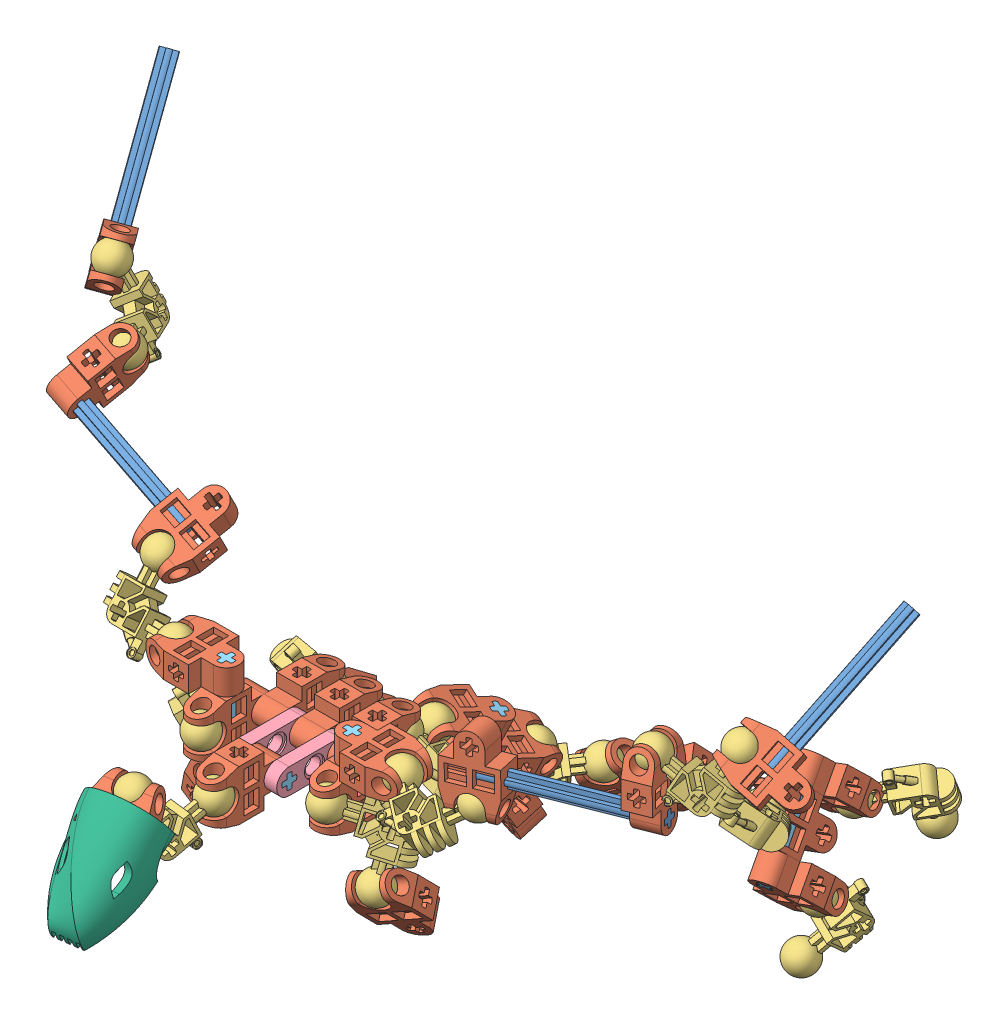
SolidWorks assembly lizard guy, configuration Default. Lengths in mm.
Overall size (163.73 140.06 167.64).
55 component instances, 6 part files, 111 mates.
Components (placement in the parent):
- cross axle 6-1: cross axle 6 [Default] at (25.195 14.8758 24.0867) x (0 1 0) z (0 0 1) size (3 30 3)
- the hand-1: the hand [Default] at (15.195 14.8758 16.5867) x (0 1 0) z (0 0 -1) size (10 5 15)
- the hand-2: the hand [Default] at (0.195 14.8758 16.5867) x (0 1 0) z (0 0 -1) size (10 5 15)
- the hand-3: the hand [Default] at (7.774 20.7052 60.2675) x (0.981668 -0.041567 -0.186012) z (-0.127151 0.584205 -0.801584) size (10 5 15)
- the hand-4: the hand [Default] at (20.195 14.8758 31.5867) x (0 -1 0) z (0 0 1) size (10 5 15)
- the hand-5: the hand [Default] at (0.195 14.8758 31.5867) x (0 1 0) z (0 0 1) size (10 5 15)
- the hand-6: the hand [Default] at (12.695 14.8758 41.5867) x (0 1 0) z (0 0 1) size (10 5 15)
- link 2x2-1: link 2x2 [Default] at (-10.1427 12.5461 28.3297) x (0.78377 0.232967 0.575701) z (0.438972 -0.863547 -0.248175) size (17.5 6 18.1)
- link 2x2-2: link 2x2 [Default] at (30.8875 12.6779 28.7903) x (-0.81925 0.219789 0.529644) z (-0.048801 -0.947003 0.317496) size (17.5 6 18.1)
- link 2x2-3: link 2x2 [Default] at (-6.8535 13.6326 11.3886) x (0.954853 0.124318 0.269818) z (0.238465 -0.862394 -0.446554) size (17.5 6 18.1)
- link 2x2-4: link 2x2 [Default] at (26.8546 10.8703 13.8459) x (-0.915958 0.400551 0.02408) z (-0.180749 -0.358261 -0.915958) size (17.5 6 18.1)
- link 2x2-5: link 2x2 [Default] at (8.6989 10.9756 53.1725) x (0.149613 0.390017 -0.908572) z (-0.159774 0.916374 0.367057) size (17.5 6 18.1)
- technic lever 3-1: technic lever 3 [Default] at (12.695 14.8758 29.0867) x (0 0 1) z (0 1 0) size (15 2.5 5)
- technic lever 3-2: technic lever 3 [Default] at (7.695 14.8758 29.0867) x (0 0 1) z (0 -1 0) size (15 2.5 5)
- cross axle 2-1: cross axle 2 [Default] at (15.195 14.8758 34.0867) x (0 1 0) z (0 0 1) size (3 10 3)
- fire mask-1: fire mask [Default] at (6.7091 14.6262 56.0059) x (0.127151 -0.584205 0.801584) z (-0.981668 0.041567 0.186012) size (20.36 10.1 15.04)
- the hand-7: the hand [Default] at (-5.4503 1.9312 5.4857) x (0.677988 -0.477303 0.55903) z (-0.284997 0.530337 0.798448) size (10 5 15)
- the hand-8: the hand [Default] at (25.2794 3.936 5.7873) x (0.950236 0.15468 0.270416) z (-0.261786 0.867016 0.423971) size (10 5 15)
- the hand-9: the hand [Default] at (-4.3992 0.6594 25.5374) x (0.201836 0.17608 -0.963462) z (0.366665 0.898587 0.241037) size (10 5 15)
- the hand-10: the hand [Default] at (31.8589 -0.0123 31.9457) x (0.887812 0.403697 -0.220948) z (-0.147993 0.705051 0.693542) size (10 5 15)
- the hand-11: the hand [Default] at (7.695 14.8758 16.5867) x (0 1 0) z (0 0 -1) size (10 5 15)
- link 2x2-6: link 2x2 [Default] at (40.5838 19.3014 34.4079) x (-0.788879 0.307438 -0.53212) z (0.611606 0.477387 -0.630904) size (17.5 6 18.1)
- link 2x2-7: link 2x2 [Default] at (10.7438 -11.7464 -18.7872) x (0.429584 0.818742 0.380945) z (0.611776 0.046426 -0.789668) size (17.5 6 18.1)
- link 2x2-8: link 2x2 [Default] at (11.8648 5.2466 11.9676) x (0.035222 0.220617 -0.974724) z (-0.166982 0.962918 0.211911) size (17.5 6 18.1)
- link 2x2-9: link 2x2 [Default] at (80.8301 36.2459 16.6695) x (-0.871411 0.443732 0.209151) z (0.368112 0.873311 -0.319094) size (17.5 6 18.1)
- the hand-12: the hand [Default] at (11.9795 4.3569 0.5296) x (0.923335 -0.236187 0.302767) z (-0.219838 0.321327 0.921097) size (10 5 15)
- the hand-13: the hand [Default] at (15.2771 -0.463 -13.2869) x (0.923335 -0.236187 0.302767) z (0.219838 -0.321327 -0.921097) size (10 5 15)
- cross axle 2-2: cross axle 2 [Default] at (20.7606 -19.465 -31.5918) x (0.800032 0.539109 -0.263268) z (-0.254023 0.701918 0.665419) size (3 10 3)
- cross axle 2-3: cross axle 2 [Default] at (15.2025 6.5321 -7.6025) x (0.219838 -0.321327 -0.921097) z (-0.923335 0.236187 -0.302767) size (3 10 3)
- cross axle 2-4: cross axle 2 [Default] at (-2.305 14.8758 29.0867) x (0 0 1) z (-1 0 0) size (3 10 3)
- the hand-15: the hand [Default] at (16.1378 -11.8732 -30.0936) x (-0.800032 -0.539109 0.263268) z (-0.254023 0.701918 0.665419) size (10 5 15)
- link 2x2-10: link 2x2 [Default] at (-22.2733 21.8189 28.5192) x (0.996833 0.055693 0.056757) z (-0.005007 0.756312 -0.654192) size (17.5 6 18.1)
- link 2x2-12: link 2x2 [Default] at (-49.6646 44.0989 -2.4655) x (0.473766 0.113514 0.873304) z (-0.515588 0.839689 0.170562) size (17.5 6 18.1)
- the hand-16: the hand [Default] at (-9.805 19.8758 29.0867) x (0 0 1) z (-1 0 0) size (10 5 15)
- the hand-17: the hand [Default] at (-21.1527 32.6196 21.1726) x (-0.943178 0.314153 -0.108271) z (-0.253699 -0.470384 0.845208) size (10 5 15)
- the hand-18: the hand [Default] at (74.7176 38.3521 18.2156) x (-0.286754 -0.097034 -0.953077) z (-0.086552 0.993413 -0.0751) size (10 5 15)
- cross axle 6-3: cross axle 6 [Default] at (-57.8431 49.9279 -3.8453) x (0.782981 -0.224686 -0.58005) z (0.582772 0.591047 0.55771) size (3 30 3)
- cross axle 6-4: cross axle 6 [Default] at (-21.5265 31.891 17.6971) x (0.214595 0.82465 0.523356) z (-0.253699 -0.470384 0.845208) size (3 30 3)
- the hand-21: the hand [Default] at (-47.9191 44.8435 8.1099) x (0.214595 0.82465 0.523356) z (0.253699 0.470384 -0.845208) size (10 5 15)
- the hand-22: the hand [Default] at (45.7666 26.3163 25.5285) x (0.954086 0.060956 -0.293263) z (0.086552 -0.993413 0.0751) size (10 5 15)
- the hand-23: the hand [Default] at (-54.3199 50.4565 -3.6043) x (-0.217527 0.774713 -0.593719) z (0.582772 0.591047 0.55771) size (10 5 15)
- the hand-24: the hand [Default] at (30.195 19.8758 29.0867) x (0 0 -1) z (1 0 0) size (10 5 15)
- cross axle 2-5: cross axle 2 [Default] at (22.695 14.8758 29.0867) x (0 0 -1) z (1 0 0) size (3 10 3)
- cross axle 2-6: cross axle 2 [Default] at (21.9084 -34.7169 -58.2829) x (0.936662 0.350234 0.000847) z (0.251484 -0.670878 -0.697624) size (3 10 3)
- cross axle 6-6: cross axle 6 [Default] at (93.311 60.9706 -11.4631) x (-0.465512 -0.66128 -0.588224) z (-0.873017 0.452281 0.182439) size (3 30 3)
- cross axle 6-7: cross axle 6 [Default] at (75.3667 30.9015 18.7789) x (0.286754 0.097034 0.953077) z (0.086552 -0.993413 0.0751) size (3 30 3)
- the hand-25: the hand [Default] at (19.9481 -22.402 -40.0749) x (-0.800032 -0.539109 0.263268) z (0.254023 -0.701918 -0.665419) size (10 5 15)
- the hand-26: the hand [Default] at (22.5758 -36.4803 -67.0973) x (-0.936662 -0.350234 -0.000847) z (0.251484 -0.670878 -0.697624) size (10 5 15)
- the hand-27: the hand [Default] at (18.9381 -33.9153 -56.5409) x (0.243763 -0.65365 0.716464) z (-0.251484 0.670878 0.697624) size (10 5 15)
- the hand-28: the hand [Default] at (25.0134 -43.0168 -59.9327) x (0.936662 0.350234 0.000847) z (0.251484 -0.670878 -0.697624) size (10 5 15)
- the hand-29: the hand [Default] at (85.53 42.1952 11.5519) x (-0.145399 -0.598457 0.787851) z (-0.873017 0.452281 0.182439) size (10 5 15)
- link 2x2-13: link 2x2 [Default] at (26.7899 -28.0518 -47.6286) x (-0.756554 0.505872 0.41439) z (-0.613887 -0.331078 -0.71661) size (17.5 6 18.1)
- link 2x2-14: link 2x2 [Default] at (29.6245 -34.5068 -77.4532) x (-0.702941 -0.201659 0.682061) z (-0.197276 -0.866059 -0.459374) size (17.5 6 18.1)
- link 2x2-15: link 2x2 [Default] at (25.9786 -53.055 -67.2798) x (0.027295 0.672693 0.739418) z (-0.429694 -0.659973 0.616278) size (17.5 6 18.1)
- cross axle 2-7: cross axle 2 [Default] at (21.9084 -34.7169 -58.2829) x (-0.936662 -0.350234 -0.000847) z (0.251484 -0.670878 -0.697624) size (3 10 3)
Mates (geometry in assembly coordinates):
- Coincident1: coincident aligned: plane of cross axle 6-1 through (25.195 14.8758 24.0867) normal (1 0 0); plane of the hand-4 through (25.195 14.8758 31.5867) normal (1 0 0)
- Concentric1: concentric anti-aligned: cylinder of cross axle 6-1 through (25.196 14.8758 24.0867) axis (-1 0 0) radius 1.5; circle of the hand-4
- Parallel1: parallel aligned: plane of cross axle 6-1 through (-4.805 15.3758 25.5867) normal (0 1 0); plane of the hand-4 through (25.195 19.8758 31.5867) normal (0 1 0)
- Coincident3: coincident aligned: plane of cross axle 6-1 through (-4.805 14.8758 24.0867) normal (-1 0 0); plane of the hand-5 through (-4.805 14.8758 31.5867) normal (-1 0 0)
- Concentric2: concentric aligned: cylinder of cross axle 6-1 through (25.196 14.8758 24.0867) axis (-1 0 0) radius 1.5; circle of the hand-5
- Parallel2: parallel aligned: plane of cross axle 6-1 through (-4.805 15.3758 25.5867) normal (0 1 0); plane of the hand-5 through (-4.805 19.8758 31.5867) normal (0 1 0)
- Coincident5: coincident anti-aligned: plane of the hand-1 through (20.195 14.8758 16.5867) normal (1 0 0); plane of the hand-4 through (20.195 14.8758 31.5867) normal (-1 0 0)
- Concentric3: concentric aligned: cylinder of cross axle 6-1 through (25.196 14.8758 24.0867) axis (-1 0 0) radius 1.5; cylinder of the hand-1 through (20.195 14.8758 24.0867) axis (-1 0 0) radius 2.5
- Coincident8: coincident aligned: plane of the hand-1 through (20.195 17.3758 16.5867) normal (0 1 0); plane of the hand-4 through (25.195 17.3758 31.5867) normal (0 1 0)
- Coincident9: coincident anti-aligned: cylinder of cross axle 6-1 through (25.196 14.8758 24.0867) axis (-1 0 0) radius 1.5; circle of the hand-2
- Coincident10: coincident aligned: plane of the hand-2 through (5.195 17.3758 16.5867) normal (0 1 0); plane of the hand-5 through (-4.805 17.3758 31.5867) normal (0 1 0)
- Coincident11: coincident anti-aligned: plane of the hand-2 through (0.195 14.8758 16.5867) normal (-1 0 0); plane of the hand-5 through (0.195 14.8758 31.5867) normal (1 0 0)
- Concentric4: concentric: sphere of the hand-4; sphere of link 2x2-2
- Concentric5: concentric: sphere of the hand-5; sphere of link 2x2-1
- Concentric6: concentric: sphere of the hand-2; sphere of link 2x2-3
- Concentric7: concentric: sphere of the hand-1; sphere of link 2x2-4
- Coincident12: coincident anti-aligned: plane of the hand-1 through (15.195 14.8758 16.5867) normal (-1 0 0); plane of technic lever 3-1 through (15.195 14.8758 29.0867) normal (1 0 0)
- Concentric8: concentric aligned: cylinder of cross axle 6-1 through (25.196 14.8758 24.0867) axis (-1 0 0) radius 1.5; cylinder of technic lever 3-1 through (13.945 14.8758 24.0867) axis (-1 0 0) radius 2.5
- Coincident13: coincident aligned: plane of the hand-1 through (20.195 17.3758 16.5867) normal (0 1 0); plane of technic lever 3-1 through (13.945 17.3758 29.0867) normal (0 1 0)
- Concentric9: concentric anti-aligned: cylinder of cross axle 6-1 through (25.196 14.8758 24.0867) axis (-1 0 0) radius 1.5; cylinder of technic lever 3-2 through (6.445 14.8758 24.0867) axis (1 0 0) radius 2.5
- Coincident14: coincident anti-aligned: plane of the hand-2 through (5.195 14.8758 16.5867) normal (1 0 0); plane of technic lever 3-2 through (5.195 14.8758 29.0867) normal (-1 0 0)
- Coincident15: coincident aligned: plane of the hand-2 through (5.195 17.3758 16.5867) normal (0 1 0); plane of technic lever 3-2 through (6.445 17.3758 29.0867) normal (0 1 0)
- Coincident16: coincident aligned: plane of technic lever 3-2 through (5.195 14.8758 29.0867) normal (-1 0 0); plane of cross axle 2-1 through (5.195 14.8758 34.0867) normal (-1 0 0)
- Concentric10: concentric anti-aligned: cylinder of technic lever 3-2 through (6.445 14.8758 34.0867) axis (1 0 0) radius 2.5; cylinder of cross axle 2-1 through (15.196 14.8758 34.0867) axis (-1 0 0) radius 1.5
- Parallel3: parallel aligned: plane of technic lever 3-2 through (6.445 17.3758 29.0867) normal (0 1 0); plane of cross axle 2-1 through (5.195 15.3758 35.5867) normal (0 1 0)
- Concentric11: concentric anti-aligned: cylinder of the hand-6 through (7.695 14.8758 34.0867) axis (1 0 0) radius 2.5; cylinder of cross axle 2-1 through (15.196 14.8758 34.0867) axis (-1 0 0) radius 1.5
- Coincident18: coincident anti-aligned: plane of the hand-6 through (7.695 14.8758 41.5867) normal (-1 0 0); plane of technic lever 3-2 through (7.695 14.8758 29.0867) normal (1 0 0)
- Coincident20: coincident aligned: plane of the hand-6 through (7.695 17.3758 41.5867) normal (0 1 0); plane of technic lever 3-1 through (13.945 17.3758 29.0867) normal (0 1 0)
- Concentric12: concentric: sphere of the hand-6; sphere of link 2x2-5
- Concentric13: concentric: sphere of the hand-3; sphere of link 2x2-5
- Parallel4: parallel: plane of the hand-3 through (7.6998 13.7315 61.4344) normal (0.127151 -0.584205 0.801584); plane of fire mask-1 through (9.0303 18.7069 67.3445) normal (-0.127151 0.584205 -0.801584)
- Concentric15: concentric: sphere of link 2x2-1; sphere of the hand-9
- Concentric16: concentric: sphere of link 2x2-2; sphere of the hand-10
- Concentric17: concentric: sphere of link 2x2-3; sphere of the hand-7
- Concentric18: concentric: sphere of link 2x2-4; sphere of the hand-8
- Concentric19: concentric aligned: circle of technic lever 3-1; circle of the hand-11
- Coincident24: coincident aligned: plane of the hand-1 through (20.195 19.8758 16.5867) normal (0 1 0); plane of the hand-11 through (12.695 19.8758 16.5867) normal (0 1 0)
- Coincident25: coincident anti-aligned: plane of technic lever 3-2 through (7.695 14.8758 29.0867) normal (1 0 0); plane of the hand-11 through (7.695 14.8758 16.5867) normal (-1 0 0)
- Concentric20: concentric: sphere of the hand-11; sphere of link 2x2-8
- Concentric21: concentric: sphere of link 2x2-8; sphere of the hand-12
- Concentric23: concentric anti-aligned: circle of the hand-12; circle of cross axle 2-3
- Coincident27: coincident aligned: plane of the hand-12 through (13.5537 8.9421 -0.6943) normal (0.314838 0.917041 -0.24477); plane of cross axle 2-3 through (15.2025 6.5321 -7.6025) normal (0.314838 0.917041 -0.24477)
- Parallel5: parallel anti-aligned: plane of the hand-12 through (14.6529 7.3355 -5.2998) normal (0.219838 -0.321327 -0.921097); plane of cross axle 2-3 through (10.5592 -2.1233 -5.1484) normal (-0.219838 0.321327 0.921097)
- Concentric24: concentric aligned: circle of the hand-13; circle of cross axle 2-3
- Coincident29: coincident aligned: plane of the hand-13 through (13.7029 -5.0482 -12.063) normal (-0.314838 -0.917041 0.24477); plane of cross axle 2-3 through (12.0541 -2.6383 -5.1548) normal (-0.314838 -0.917041 0.24477)
- Coincident31: coincident aligned: plane of the hand-12 through (18.1704 7.7612 0.8196) normal (0.923335 -0.236187 0.302767); plane of the hand-13 through (18.3196 -6.2292 -10.5492) normal (0.923335 -0.236187 0.302767)
- Concentric25: concentric: sphere of link 2x2-7; sphere of the hand-13
- Concentric26: concentric: sphere of link 2x2-7; sphere of the hand-15
- Concentric28: concentric anti-aligned: circle of cross axle 2-4; cylinder of the hand-16 through (-2.305 24.8758 29.0867) axis (0 -1 0) radius 2.5
- Coincident35: coincident aligned: plane of cross axle 2-4 through (-2.305 24.8758 29.0867) normal (0 1 0); plane of the hand-16 through (-9.805 24.8758 29.0867) normal (0 1 0)
- Parallel7: parallel aligned: plane of cross axle 2-4 through (-3.805 24.8758 29.5867) normal (0 0 1); plane of the hand-16 through (-9.805 24.8758 34.0867) normal (0 0 1)
- Coincident37: coincident anti-aligned: plane of the hand-5 through (-4.805 19.8758 31.5867) normal (0 1 0); plane of the hand-16 through (-9.805 19.8758 29.0867) normal (0 -1 0)
- Concentric29: concentric anti-aligned: cylinder of the hand-5 through (-2.305 19.8758 29.0867) axis (0 -1 0) radius 1.5; circle of the hand-16
- Coincident40: coincident aligned: plane of the hand-5 through (-4.805 14.8758 26.5867) normal (0 0 -1); plane of the hand-16 through (-9.805 24.8758 26.5867) normal (0 0 -1)
- Concentric30: concentric: sphere of link 2x2-10; sphere of the hand-16
- Concentric31: concentric: sphere of link 2x2-10; sphere of the hand-17
- Concentric32: concentric anti-aligned: cylinder of the hand-17 through (-25.7708 33.3047 17.2099) axis (0.943178 -0.314153 0.108271) radius 1.5; cylinder of cross axle 6-4 through (-21.5256 31.8907 17.6972) axis (-0.943178 0.314153 -0.108271) radius 1.5
- Coincident41: coincident anti-aligned: plane of the hand-17 through (-22.4612 29.5605 19.0774) normal (-0.943178 0.314153 -0.108271); plane of cross axle 6-4 through (-21.5265 31.891 17.6971) normal (0.943178 -0.314153 0.108271)
- Parallel8: parallel anti-aligned: plane of the hand-17 through (-22.2257 28.4963 18.5558) normal (-0.214595 -0.82465 -0.523356); plane of cross axle 6-4 through (-50.0951 41.0223 15.9784) normal (0.214595 0.82465 0.523356)
- Concentric35: concentric anti-aligned: cylinder of cross axle 6-4 through (-21.5256 31.8907 17.6972) axis (-0.943178 0.314153 -0.108271) radius 1.5; circle of the hand-21
- Coincident50: coincident aligned: plane of cross axle 6-4 through (-49.8219 41.3156 14.449) normal (-0.943178 0.314153 -0.108271); plane of the hand-21 through (-47.9191 44.8435 8.1099) normal (-0.943178 0.314153 -0.108271)
- Parallel12: parallel aligned: plane of cross axle 6-4 through (-50.0951 41.0223 15.9784) normal (0.214595 0.82465 0.523356); plane of the hand-21 through (-42.6667 45.3343 9.9596) normal (0.214595 0.82465 0.523356)
- Concentric36: concentric: sphere of link 2x2-12; sphere of the hand-21
- Concentric37: concentric: sphere of link 2x2-12; sphere of the hand-23
- Coincident52: coincident anti-aligned: plane of cross axle 6-3 through (-57.8431 49.9279 -3.8453) normal (0.217527 -0.774713 0.593719); plane of the hand-23 through (-57.4823 51.7201 -1.6389) normal (-0.217527 0.774713 -0.593719)
- Concentric38: concentric anti-aligned: cylinder of cross axle 6-3 through (-57.8429 49.9271 -3.8447) axis (-0.217527 0.774713 -0.593719) radius 1.5; cylinder of the hand-23 through (-58.822 53.4141 -6.517) axis (0.217527 -0.774713 0.593719) radius 1.5
- Parallel13: parallel aligned: plane of cross axle 6-3 through (-65.8347 73.2108 -21.0656) normal (-0.582772 -0.591047 -0.55771); plane of the hand-23 through (-61.1487 48.6247 -3.4926) normal (-0.582772 -0.591047 -0.55771)
- Coincident53: coincident aligned: plane of the hand-24 through (30.195 24.8758 29.0867) normal (0 1 0); plane of cross axle 2-5 through (22.695 24.8758 29.0867) normal (0 1 0)
- Coincident54: coincident aligned: circle of the hand-24; circle of cross axle 2-5
- Parallel14: parallel aligned: plane of the hand-24 through (30.195 24.8758 26.5867) normal (0 0 -1); plane of cross axle 2-5 through (24.195 24.8758 28.5867) normal (0 0 -1)
- Concentric39: concentric aligned: circle of the hand-4; circle of the hand-24
- Coincident56: coincident anti-aligned: plane of the hand-4 through (25.195 19.8758 31.5867) normal (0 1 0); plane of the hand-24 through (30.195 19.8758 29.0867) normal (0 -1 0)
- Coincident57: coincident aligned: plane of the hand-4 through (25.195 14.8758 26.5867) normal (0 0 -1); plane of the hand-24 through (30.195 24.8758 26.5867) normal (0 0 -1)
- Concentric40: concentric: sphere of link 2x2-6; sphere of the hand-24
- Concentric41: concentric: sphere of link 2x2-6; sphere of the hand-22
- Coincident58: coincident anti-aligned: plane of the hand-22 through (47.362 26.7252 29.0988) normal (0.954086 0.060956 -0.293263); plane of cross axle 6-7 through (46.7441 29.0728 27.5768) normal (-0.954086 -0.060956 0.293263)
- Coincident59: coincident aligned: circle of the hand-22; cylinder of cross axle 6-7 through (75.3677 30.9016 18.7786) axis (-0.954086 -0.060956 0.293263) radius 1.5
- Parallel15: parallel aligned: plane of the hand-22 through (47.2003 26.8014 30.2939) normal (0.286754 0.097034 0.953077); plane of cross axle 6-7 through (47.0173 27.6312 28.166) normal (0.286754 0.097034 0.953077)
- Concentric42: concentric anti-aligned: cylinder of the hand-18 through (70.5963 30.5967 20.2452) axis (0.954086 0.060956 -0.293263) radius 2.5; cylinder of cross axle 6-7 through (75.3677 30.9016 18.7786) axis (-0.954086 -0.060956 0.293263) radius 1.5
- Parallel16: parallel anti-aligned: plane of the hand-18 through (70.3799 33.0803 20.0574) normal (0.086552 -0.993413 0.0751); plane of cross axle 6-7 through (46.2707 29.424 26.1096) normal (-0.086552 0.993413 -0.0751)
- Coincident63: coincident aligned: plane of the hand-18 through (74.7176 38.3521 18.2156) normal (0.954086 0.060956 -0.293263); plane of cross axle 6-7 through (75.3667 30.9015 18.7789) normal (0.954086 0.060956 -0.293263)
- Concentric43: concentric: sphere of link 2x2-9; sphere of the hand-18
- Concentric44: concentric: sphere of link 2x2-9; sphere of the hand-29
- Coincident64: coincident anti-aligned: plane of cross axle 6-6 through (88.949 43.0169 12.1725) normal (-0.145399 -0.598457 0.787851); plane of the hand-29 through (87.4182 45.0734 13.4521) normal (0.145399 0.598457 -0.787851)
- Concentric45: concentric anti-aligned: cylinder of cross axle 6-6 through (93.3111 60.9712 -11.4638) axis (-0.145399 -0.598457 0.787851) radius 1.5; cylinder of the hand-29 through (88.1493 39.7254 16.5056) axis (0.145399 0.598457 -0.787851) radius 1.5
- Parallel17: parallel aligned: plane of cross axle 6-6 through (90.0838 43.7827 12.9636) normal (0.873017 -0.452281 -0.182439); plane of the hand-29 through (92.2226 43.2401 13.5808) normal (0.873017 -0.452281 -0.182439)
- Coincident66: coincident aligned: plane of cross axle 2-2 through (20.7606 -19.465 -31.5918) normal (0.543526 -0.465481 0.698503); plane of the hand-15 through (18.8554 -14.2006 -26.6011) normal (0.543526 -0.465481 0.698503)
- Concentric46: concentric aligned: cylinder of cross axle 2-2 through (20.7611 -19.4654 -31.5911) axis (-0.543526 0.465481 -0.698503) radius 1.5; cylinder of the hand-15 through (20.7606 -19.465 -31.5918) axis (-0.543526 0.465481 -0.698503) radius 2.5
- Parallel18: parallel aligned: plane of cross axle 2-2 through (14.2523 -15.9698 -38.5146) normal (0.254023 -0.701918 -0.665419); plane of the hand-15 through (20.1255 -17.7102 -29.9282) normal (0.254023 -0.701918 -0.665419)
- Coincident68: coincident anti-aligned: plane of the hand-15 through (16.1378 -11.8732 -30.0936) normal (-0.543526 0.465481 -0.698503); plane of the hand-25 through (19.9481 -22.402 -40.0749) normal (0.543526 -0.465481 0.698503)
- Concentric47: concentric anti-aligned: cylinder of the hand-15 through (20.7606 -19.465 -31.5918) axis (-0.543526 0.465481 -0.698503) radius 2.5; cylinder of the hand-25 through (15.3253 -14.8102 -38.5768) axis (0.543526 -0.465481 0.698503) radius 2.5
- Coincident69: coincident aligned: plane of the hand-15 through (20.8555 -12.8528 -27.2593) normal (0.800032 0.539109 -0.263268); plane of the hand-25 through (19.2306 -18.7268 -44.2256) normal (0.800032 0.539109 -0.263268)
- Concentric48: concentric: sphere of the hand-25; sphere of link 2x2-13
- Concentric49: concentric: sphere of the hand-27; sphere of link 2x2-13
- Coincident70: coincident aligned: plane of cross axle 2-6 through (24.3461 -41.2535 -51.1182) normal (0.243763 -0.65365 0.716464); plane of the hand-28 through (26.2322 -46.285 -56.3504) normal (0.243763 -0.65365 0.716464)
- Concentric50: concentric aligned: cylinder of cross axle 2-6 through (21.9082 -34.7163 -58.2836) axis (0.243763 -0.65365 0.716464) radius 1.5; circle of the hand-28
- Parallel19: parallel aligned: plane of cross axle 2-6 through (22.8153 -41.4434 -50.7707) normal (-0.251484 0.670878 0.697624); plane of the hand-28 through (24.9748 -42.9306 -52.8623) normal (-0.251484 0.670878 0.697624)
- Concentric51: concentric aligned: cylinder of the hand-27 through (23.1273 -37.9852 -54.7005) axis (-0.243763 0.65365 -0.716464) radius 1.5; cylinder of the hand-28 through (24.3461 -41.2535 -51.1182) axis (-0.243763 0.65365 -0.716464) radius 2.5
- Coincident72: coincident anti-aligned: plane of the hand-27 through (24.8402 -35.4324 -52.9544) normal (0.243763 -0.65365 0.716464); plane of the hand-28 through (25.0134 -43.0168 -59.9327) normal (-0.243763 0.65365 -0.716464)
- Coincident73: coincident aligned: plane of the hand-27 through (23.6214 -32.1642 -56.5367) normal (0.936662 0.350234 0.000847); plane of the hand-28 through (28.5739 -45.4095 -56.3483) normal (0.936662 0.350234 0.000847)
- Coincident74: coincident aligned: plane of the hand-26 through (21.3569 -33.212 -70.6797) normal (-0.243763 0.65365 -0.716464); plane of cross axle 2-7 through (19.4708 -28.1804 -65.4475) normal (-0.243763 0.65365 -0.716464)
- Concentric52: concentric anti-aligned: cylinder of the hand-26 through (19.4708 -28.1804 -65.4475) axis (0.243763 -0.65365 0.716464) radius 2.5; cylinder of cross axle 2-7 through (21.9087 -34.7176 -58.2821) axis (-0.243763 0.65365 -0.716464) radius 1.5
- Parallel20: parallel aligned: plane of the hand-26 through (20.0995 -29.8576 -67.1916) normal (-0.251484 0.670878 0.697624); plane of cross axle 2-7 through (20.7501 -27.3197 -65.0974) normal (-0.251484 0.670878 0.697624)
- Coincident76: coincident anti-aligned: plane of the hand-26 through (22.5758 -36.4803 -67.0973) normal (0.243763 -0.65365 0.716464); plane of the hand-27 through (22.4026 -28.8959 -60.119) normal (-0.243763 0.65365 -0.716464)
- Concentric53: concentric anti-aligned: cylinder of the hand-26 through (19.4708 -28.1804 -65.4475) axis (0.243763 -0.65365 0.716464) radius 2.5; cylinder of the hand-27 through (23.1273 -37.9852 -54.7005) axis (-0.243763 0.65365 -0.716464) radius 1.5
- Coincident77: coincident aligned: plane of the hand-26 through (19.0153 -34.0876 -70.6818) normal (-0.936662 -0.350234 -0.000847); plane of the hand-27 through (18.9381 -33.9153 -56.5409) normal (-0.936662 -0.350234 -0.000847)
- Concentric54: concentric: sphere of the hand-26; sphere of link 2x2-14
- Concentric55: concentric: sphere of the hand-28; sphere of link 2x2-15
- Coincident78: coincident: plane of the hand-3 through (7.064 16.6525 57.4265) normal (-0.141989 -0.810541 -0.56821); plane of fire mask-1 through (7.064 16.6525 57.4265) normal (-0.141989 -0.810541 -0.56821)
- Concentric56: concentric: cylinder of the hand-3 through (8.0177 12.271 63.4384) axis (0.141989 0.810541 0.56821) radius 2.5; cylinder of fire mask-1 through (9.0939 18.4148 67.7453) axis (-0.141989 -0.810541 -0.56821) radius 1.5
- Parallel21: parallel anti-aligned: plane of the hand-3 through (7.6998 13.7315 61.4344) normal (0.127151 -0.584205 0.801584); plane of fire mask-1 through (9.0303 18.7069 67.3445) normal (-0.127151 0.584205 -0.801584)
